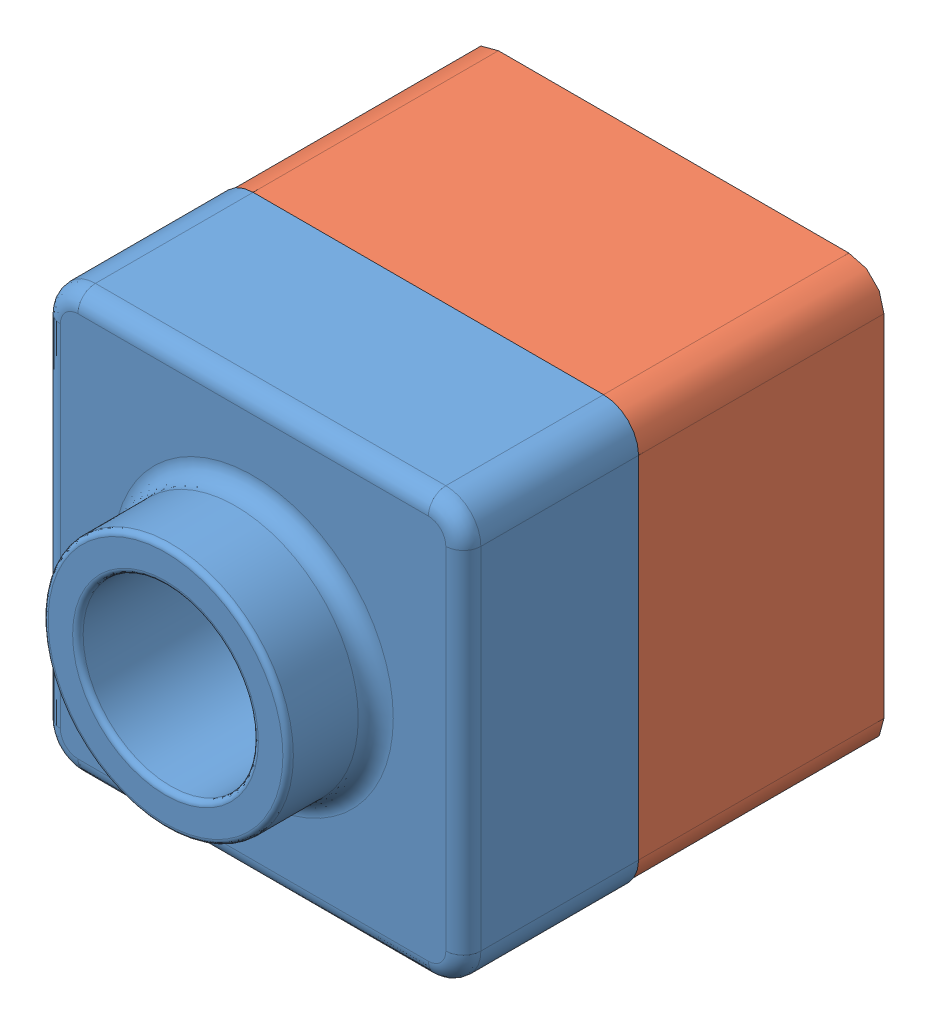
SolidWorks assembly 9.1.1 assembly, configuration Default. Lengths in mm.
Overall size (120 120 145).
2 component instances, 2 part files, 3 mates.
Components (placement in the parent):
- 9.1.1-1: 9.1.1 [Default] at origin size (120 120 75)
- 9.2.1 part-1: 9.2.1 part [Default] at (-60 -60 -70) size (120 120 90)
Mates (geometry in assembly coordinates):
- Coincident3: coincident: point of 9.1.1-1; point of 9.2.1 part-1
- Coincident4: coincident: moEndPointRef_w of 9.1.1-1; moEndPointRef_w of 9.2.1 part-1
- Coincident5: coincident: moEndPointRef_w of 9.1.1-1; moEndPointRef_w of 9.2.1 part-1
